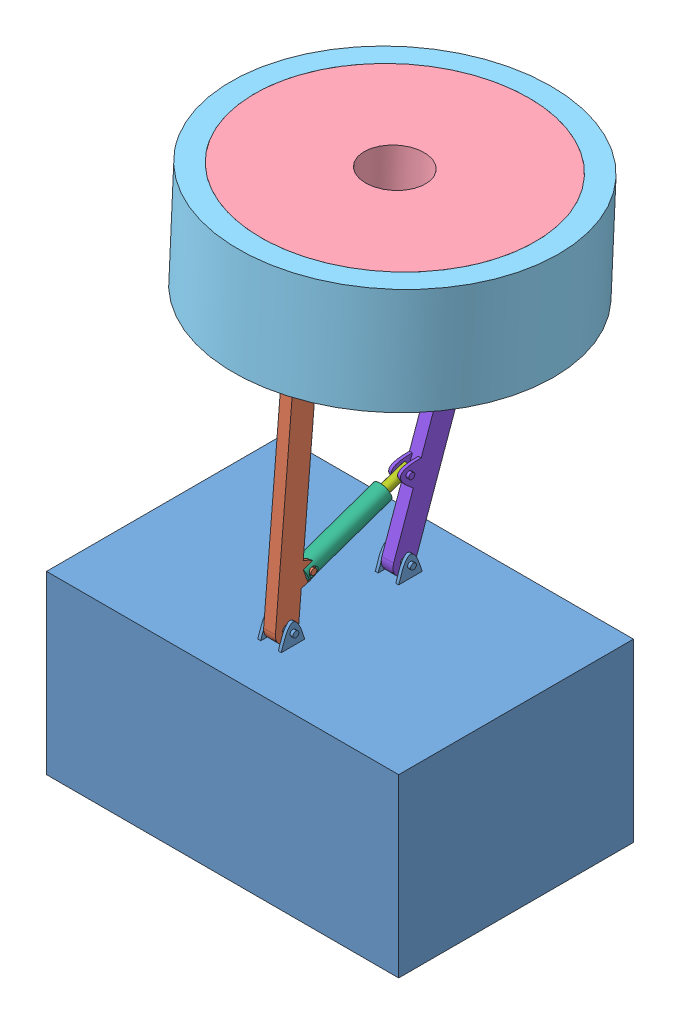
SolidWorks assembly suspensionAssembly, configuration Default. Lengths in mm.
Overall size (745.53 916.66 753.21).
8 component instances, 8 part files, 15 mates.
Components (placement in the parent):
- chassisSimplified-1: chassisSimplified [Default] at (600 -130.4506 18.2448) size (600 335.18 400)
- arm1-1: arm1 [Default] at (590 238.4256 101.5501) x (0 0.996439 -0.084314) z (1 0 0) size (440 70 30)
- wheelhub-1: wheelhub [Default] at (600 466.4765 -67.8737) x (1 0 0) z (0 0.048055 0.998845) size (116.53 100.65 400)
- rim-1: rim [Default] at (600 618.3009 -75.1781) x (0.945079 -0.015706 -0.326463) z (0 -0.998845 0.048055) size (457.2 457.2 127)
- tire-1: tire [Default] at (600 618.3009 -75.1781) x (-0.806617 0.028404 0.590392) z (0 -0.998845 0.048055) size (533.4 533.4 177.8)
- cylinder-1: cylinder [Default] at (600 151.8821 -54.6109) x (1 0 0) z (0 -0.328176 0.944617) size (30 30 150)
- piston-1: piston [Default] at (600 166.7396 -97.3763) x (1 0 0) z (0 -0.328176 0.944617) size (15 15 100)
- arm2-1: arm2 [Default] at (610 227.5166 -149.1048) x (0 0.941895 -0.335909) z (-1 0 0) size (440 70 30)
Mates (geometry in assembly coordinates):
- Hub_Rim_coi: coincident anti-aligned: plane of wheelhub-1 through (600 491.4476 -69.0751) normal (0 0.998845 -0.048055); plane of rim-1 through (600 491.4476 -69.0751) normal (0 -0.998845 0.048055)
- Hub_Rim_con: concentric anti-aligned: cylinder of wheelhub-1 through (600 511.4245 -70.0362) axis (0 -0.998845 0.048055) radius 50; cylinder of rim-1 through (600 491.4476 -69.0751) axis (0 0.998845 -0.048055) radius 50
- Rim_Tire_con: concentric aligned: cylinder of rim-1 through (600 491.4476 -69.0751) axis (0 0.998845 -0.048055) radius 228.6; cylinder of tire-1 through (600 440.7063 -66.6339) axis (0 0.998845 -0.048055) radius 228.6
- Rim_Tire_coi: coincident aligned: plane of rim-1 through (600 618.3009 -75.1781) normal (0 0.998845 -0.048055); plane of tire-1 through (600 618.3009 -75.1781) normal (0 0.998845 -0.048055)
- Cyl_Pst_con: concentric aligned: cylinder of cylinder-1 through (600 102.6557 87.0816) axis (0 0.328176 -0.944617) radius 7.5; cylinder of piston-1 through (600 133.922 -2.9146) axis (0 0.328176 -0.944617) radius 7.5
- Cyl_Arm1_con: concentric aligned: cylinder of arm1-1 through (585 105.9375 77.6355) axis (1 0 0) radius 5; cylinder of cylinder-1 through (585 105.9375 77.6355) axis (1 0 0) radius 7.5
- Ch_Arm1_con: concentric aligned: cylinder of chassisSimplified-1 through (600 39.1377 118.4128) axis (1 0 0) radius 5; cylinder of arm1-1 through (590 39.1377 118.4128) axis (1 0 0) radius 7.5
- Ch_Arm1_dst: distance = 10 mm aligned: plane of arm1-1 through (610 39.1377 118.4128) normal (1 0 0); plane of chassisSimplified-1 through (620 54.7341 118.2448) normal (1 0 0)
- Arm2_Pst_con: concentric anti-aligned: cylinder of piston-1 through (592.5 163.9219 -89.2658) axis (1 0 0) radius 5.5; cylinder of arm2-1 through (615 163.9219 -89.2658) axis (-1 0 0) radius 5
- Ch_Arm2_con: concentric anti-aligned: cylinder of chassisSimplified-1 through (600 39.1377 -81.9231) axis (1 0 0) radius 5; cylinder of arm2-1 through (610 39.1377 -81.9231) axis (-1 0 0) radius 7.5
- Ch_Arm2_dst: distance = 10 mm aligned: plane of chassisSimplified-1 through (620 54.7341 -81.7552) normal (1 0 0); plane of arm2-1 through (610 39.1377 -81.9231) normal (1 0 0)
- Arm2_Hub_con: concentric anti-aligned: cylinder of wheelhub-1 through (575 415.8955 -216.2866) axis (1 0 0) radius 5; cylinder of arm2-1 through (610 415.8955 -216.2866) axis (-1 0 0) radius 7.5
- Arm1_Hub_con: concentric aligned: cylinder of arm1-1 through (590 437.7134 84.6873) axis (1 0 0) radius 7.5; cylinder of wheelhub-1 through (575 437.7134 84.6873) axis (1 0 0) radius 5
- Arm1_Cyl_coi: coincident aligned: plane of arm1-1 through (600 238.4256 101.5501) normal (1 0 0); plane of cylinder-1
- Arm1_Hub_dst: distance = 10 mm aligned: plane of arm1-1 through (610 39.1377 118.4128) normal (1 0 0); plane of wheelhub-1 through (620 428.0925 84.1465) normal (1 0 0)
